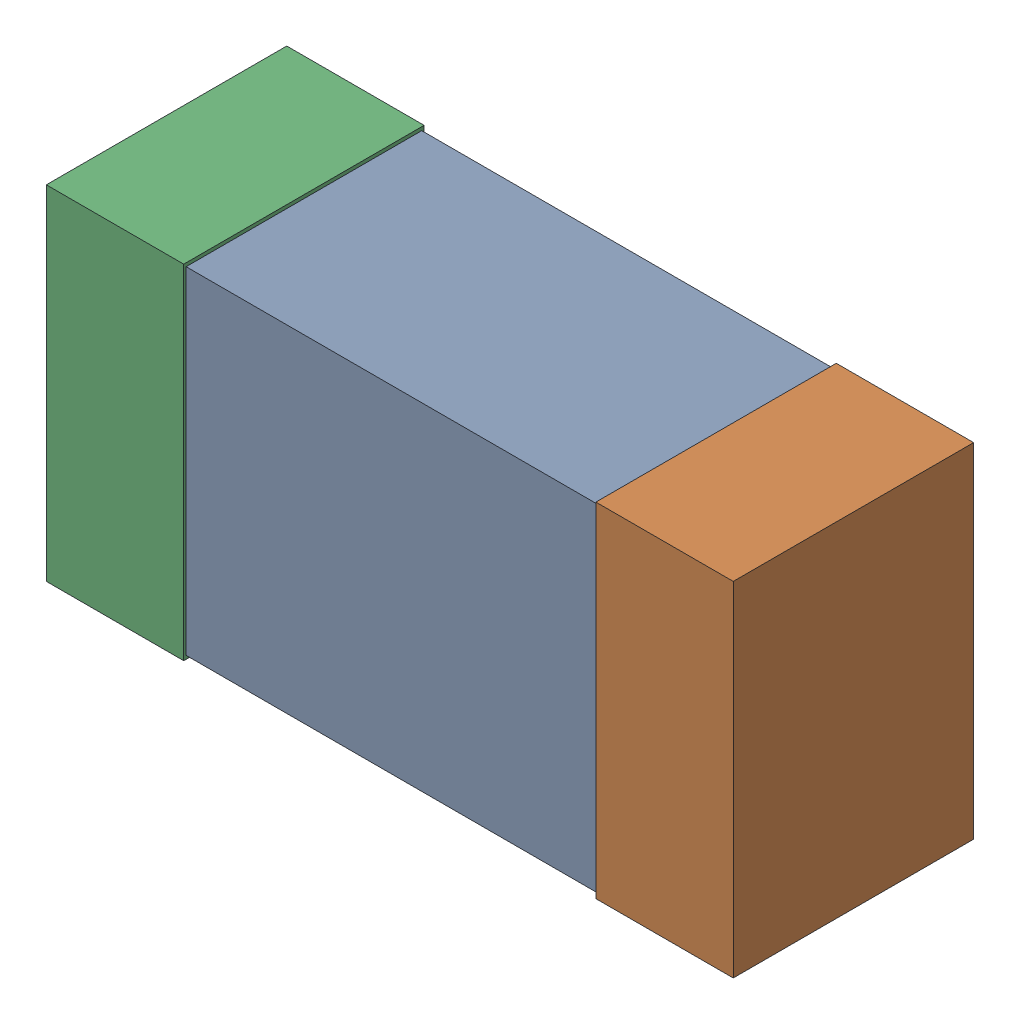
SolidWorks assembly 6074689680, configuration Predeterminado. Lengths in mm.
Overall size (1 0.5 0.35).
3 component instances, 3 part files, 0 mates.
Components (placement in the parent):
- body-2-1: body-2 [Predeterminado] at (-0.3 -0.245 0.0035) size (0.6 0.49 0.34)
- term2-1-1: term2-1 [Predeterminado] at (0.3 -0.25 0) size (0.2 0.5 0.35)
- term1-1-1: term1-1 [Predeterminado] at (-0.5 -0.25 0) size (0.2 0.5 0.35)
